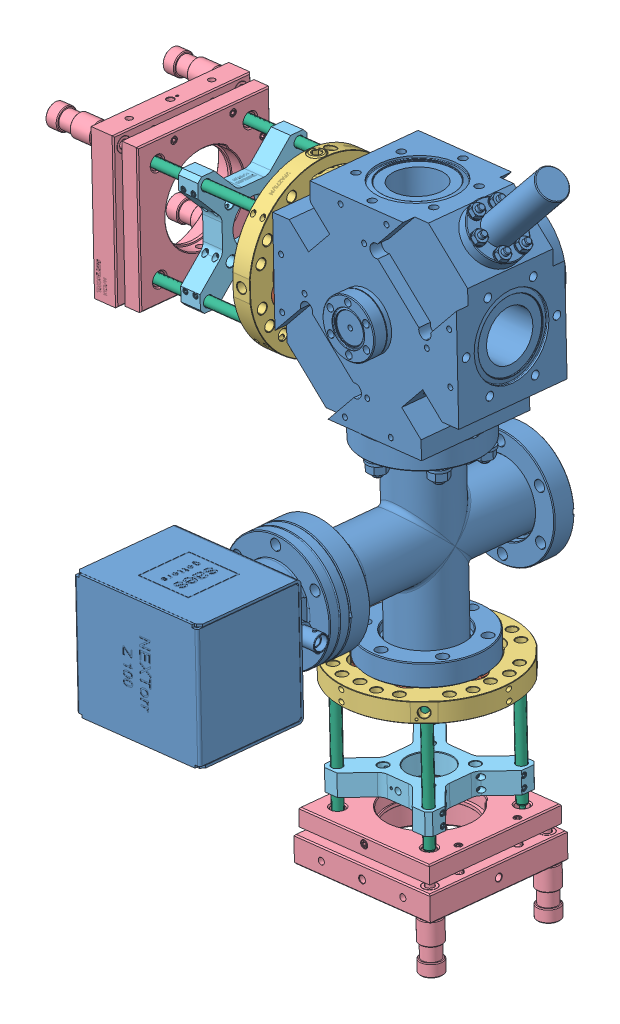
SolidWorks assembly 2DMOTopticsChamber, configuration Standard. Lengths in mm.
Overall size (319.37 449.09 275.08).
17 component instances, 6 part files, 27 mates.
Components (placement in the parent):
- 2D_MOT_Na-1: 2D_MOT_Na [Standard] at (-423.0199 174.1812 -558.2531) x (0.993572 0.113203 0) z (-0.009915 0.087024 0.996157) size (155.3 280.3 251.5)
- CF40-1: CF40 [Standard] at (-362.1599 71.9376 -548.7154) x (-0.993572 -0.113203 0) z (0.104625 -0.918284 -0.381849) size (12.7 69.35 69.34)
- CF40-2: CF40 [Standard] at (-281.6835 -104.3746 -532.5118) x (0.112768 -0.989753 0.087587) z (-0.000039 0.088145 0.996108) size (12.7 69.35 69.34)
- flangeAdapter-1: flangeAdapter [Default] at (-367.8382 71.2906 -548.7154) x (-0.008882 0.077955 0.996917) z (-0.993572 -0.113203 0) size (100.8 102.1 11.43)
- KC2_M-Solidworks-1: KC2_M-Solidworks [Default] at (-471.1735 59.5171 -548.7154) x (-0.009915 0.087024 0.996157) z (0.993572 0.113203 0) size (89.03 89.03 58.51)
- LCP02_M-Solidworks-1: LCP02_M-Solidworks [Default] at (-416.8257 65.7092 -548.7154) x (-0.009915 0.087024 0.996157) z (-0.993572 -0.113203 0) size (70.75 70.61 12.7)
- ER3-Solidworks-1: ER3-Solidworks [Default] at (-409.6675 98.6888 -522.9064) x (0.104625 -0.918284 -0.381849) z (-0.043227 0.379395 -0.924225) size (5.99 81.28 5.99)
- ER3-Solidworks-2: ER3-Solidworks [Default] at (-402.969 39.8969 -517.7534) x (0.080087 -0.702917 -0.706748) z (-0.080006 0.702205 -0.707465) size (5.99 81.28 5.99)
- ER3-Solidworks-3: ER3-Solidworks [Default] at (-402.3646 34.592 -574.4222) x (-0.080087 0.702917 0.706748) z (0.080006 -0.702205 0.707465) size (5.99 81.28 5.99)
- ER3-Solidworks-4: ER3-Solidworks [Default] at (-409.1402 94.0605 -582.7779) x (0.080087 -0.702917 -0.706748) z (-0.080006 0.702205 -0.707465) size (5.99 81.28 5.99)
- KC2_M-Solidworks-2: KC2_M-Solidworks [Default] at (-269.5474 -210.892 -523.0857) x (-0.993572 -0.113203 0) z (-0.112768 0.989753 -0.087587) size (89.03 89.03 58.51)
- ER3-Solidworks-5: ER3-Solidworks [Default] at (-308.3671 -147.1898 -499.6715) x (-0.241066 -0.112768 -0.963935) z (-0.963935 -0.087587 0.251312) size (5.99 81.28 5.99)
- ER3-Solidworks-6: ER3-Solidworks [Default] at (-248.8876 -140.56 -558.7901) x (-0.822124 -0.142447 -0.5512) z (-0.558029 0.009849 0.829763) size (5.99 81.28 5.99)
- ER3-Solidworks-7: ER3-Solidworks [Default] at (-305.2277 -153.2743 -557.4645) x (0.993609 0.112768 -0.004964) z (-0.004964 0.087587 0.996145) size (5.99 81.28 5.99)
- ER3-Solidworks-8: ER3-Solidworks [Default] at (-249.1653 -136.7775 -499.9919) x (-0.241066 -0.112768 -0.963935) z (-0.963935 -0.087587 0.251312) size (5.99 81.28 5.99)
- flangeAdapter-2: flangeAdapter [Default] at (-281.1689 -108.8913 -532.1121) x (-0.724255 -0.021529 0.689196) z (0.112768 -0.989753 0.087587) size (100.8 102.1 11.43)
- LCP02_M-Solidworks-2: LCP02_M-Solidworks [Default] at (-274.5287 -167.1714 -526.9547) x (-0.993572 -0.113203 0) z (0.112768 -0.989753 0.087587) size (70.75 70.61 12.7)
Mates (geometry in assembly coordinates):
- Deckungsgleich1: coincident: plane of 2D_MOT_Na-1 through (-360.4177 66.9257 -607.5936) normal (-0.993572 -0.113203 0); plane of CF40-1 through (-361.0126 72.1472 -547.8242) normal (0.993572 0.113203 0)
- Konzentrisch1: concentric: cylinder of 2D_MOT_Na-1 through (-241.784 85.7316 -547.8242) axis (-0.993572 -0.113203 0) radius 15; circle of CF40-1
- Deckungsgleich2: coincident: plane of 2D_MOT_Na-1 through (-265.7414 -104.7143 -556.8761) normal (0.112768 -0.989753 0.087587); plane of CF40-2 through (-280.5362 -104.165 -531.6206) normal (-0.112768 0.989753 -0.087587)
- Konzentrisch2: concentric: cylinder of 2D_MOT_Na-1 through (-287.5842 -42.3054 -537.0948) axis (-0.112768 0.989753 -0.087587) radius 18.5; cylinder of CF40-2 through (-280.3958 -105.3969 -531.5116) axis (-0.112768 0.989753 -0.087587) radius 12.9921
- Deckungsgleich3: coincident: plane of 2D_MOT_Na-1 through (-360.4177 66.9257 -607.5936) normal (-0.993572 -0.113203 0); plane of flangeAdapter-1 through (-361.0126 72.1472 -547.8242) normal (0.993572 0.113203 0)
- Konzentrisch3: concentric: cylinder of CF40-1 through (-373.6309 70.7095 -547.8242) axis (0.993572 0.113203 0) radius 34.671; cylinder of flangeAdapter-1 through (-372.3691 70.8533 -547.8242) axis (0.993572 0.113203 0) radius 50.8
- Konzentrisch4: concentric: circle of KC2_M-Solidworks-1; cylinder of ER3-Solidworks-1 through (-450.0643 94.7236 -520.5672) axis (-0.993572 -0.113203 0) radius 2.9972
- Konzentrisch5: concentric: cylinder of KC2_M-Solidworks-1 through (-439.0745 35.8198 -515.312) axis (-0.993572 -0.113203 0) radius 3.9624; cylinder of ER3-Solidworks-2 through (-443.2982 35.3385 -515.312) axis (-0.993572 -0.113203 0) radius 2.9972
- Konzentrisch6: concentric: cylinder of KC2_M-Solidworks-1 through (-438.4796 30.5983 -575.0813) axis (-0.993572 -0.113203 0) radius 3.9624; cylinder of ER3-Solidworks-3 through (-442.7033 30.1171 -575.0813) axis (-0.993572 -0.113203 0) radius 2.9972
- Konzentrisch7: concentric: cylinder of KC2_M-Solidworks-1 through (-445.2457 89.9834 -580.3365) axis (-0.993572 -0.113203 0) radius 3.9624; cylinder of ER3-Solidworks-4 through (-449.4693 89.5022 -580.3365) axis (-0.993572 -0.113203 0) radius 2.9972
- Deckungsgleich5: coincident: plane of ER3-Solidworks-3 through (-367.2128 40.6714 -573.1425) normal (0.993572 0.113203 0); plane of ER3-Solidworks-4 through (-373.5395 96.2 -582.2752) normal (0.993572 0.113203 0)
- Deckungsgleich6: coincident: plane of ER3-Solidworks-1 through (-374.0671 100.8307 -521.6147) normal (0.993572 0.113203 0); plane of ER3-Solidworks-4 through (-373.5395 96.2 -582.2752) normal (0.993572 0.113203 0)
- Deckungsgleich7: coincident: plane of ER3-Solidworks-1 through (-374.0671 100.8307 -521.6147) normal (0.993572 0.113203 0); plane of ER3-Solidworks-2 through (-367.3683 42.0364 -517.2507) normal (0.993572 0.113203 0)
- Konzentrisch8: concentric: circle of CF40-1; cylinder of KC2_M-Solidworks-1 through (-450.2358 61.9815 -547.8242) axis (0.993572 0.113203 0) radius 25.527
- Parallel1: parallel: plane of 2D_MOT_Na-1 through (-301.0512 75.8935 -582.6897) normal (0.009915 -0.087024 -0.996157); plane of KC2_M-Solidworks-1 through (-450.587 13.4574 -588.2102) normal (0.009915 -0.087024 -0.996157)
- Konzentrisch9: concentric: circle of KC2_M-Solidworks-1; cylinder of LCP02_M-Solidworks-1 through (-410.5253 66.5059 -547.8242) axis (-0.993572 -0.113203 0) radius 13.1445
- Konzentrisch10: concentric: circle of LCP02_M-Solidworks-1; cylinder of ER3-Solidworks-3 through (-442.7033 30.1171 -575.0813) axis (-0.993572 -0.113203 0) radius 2.9972
- Konzentrisch11: concentric: cylinder of CF40-2 through (-279.104 -116.7349 -530.5083) axis (-0.112768 0.989753 -0.087587) radius 34.671; circle of KC2_M-Solidworks-2
- Parallel2: parallel: plane of 2D_MOT_Na-1 through (-301.0512 75.8935 -582.6897) normal (0.009915 -0.087024 -0.996157); plane of KC2_M-Solidworks-2 through (-225.5136 -194.4349 -567.8085) normal (0.009915 -0.087024 -0.996157)
- Deckungsgleich10: coincident: circle of KC2_M-Solidworks-2; cone of ER3-Solidworks-5 through (-301.3861 -186.1772 -494.5479) axis (0.112768 -0.989753 0.087587)
- Deckungsgleich11: coincident: circle of KC2_M-Solidworks-2; plane of ER3-Solidworks-8 through (-242.0984 -176.5191 -494.8016) normal (0.112768 -0.989753 0.087587)
- Konzentrisch12: concentric: circle of KC2_M-Solidworks-2; circle of ER3-Solidworks-7
- Konzentrisch13: concentric: circle of KC2_M-Solidworks-2; circle of ER3-Solidworks-6
- Konzentrisch14: concentric: cylinder of CF40-2 through (-279.104 -116.7349 -530.5083) axis (-0.112768 0.989753 -0.087587) radius 34.671; cylinder of flangeAdapter-2 through (-279.3771 -114.3381 -530.7204) axis (-0.112768 0.989753 -0.087587) radius 50.8
- Konzentrisch15: concentric: cylinder of KC2_M-Solidworks-2 through (-270.7774 -189.8164 -524.041) axis (-0.112768 0.989753 -0.087587) radius 25.527; cylinder of LCP02_M-Solidworks-2 through (-274.0975 -160.6768 -526.6197) axis (0.112768 -0.989753 0.087587) radius 13.1445
- Konzentrisch16: concentric: cylinder of ER3-Solidworks-7 through (-309.7106 -113.1135 -561.245) axis (-0.112768 0.989753 -0.087587) radius 2.9972; circle of LCP02_M-Solidworks-2
- Konzentrisch17: concentric: circle of KC2_M-Solidworks-2; cylinder of ER3-Solidworks-8 through (-242.0984 -176.5191 -494.8016) axis (0.112768 -0.989753 0.087587) radius 2.9972
